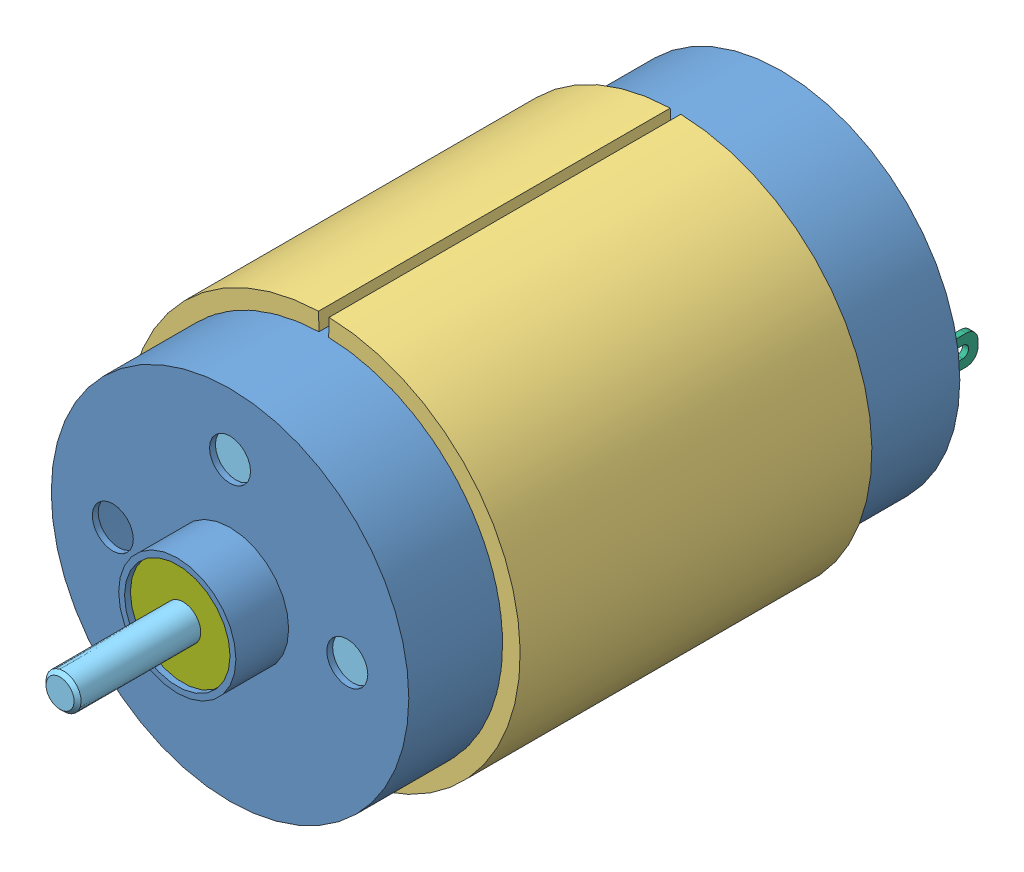
SolidWorks assembly motor 12v, configuration Default. Lengths in mm.
Overall size (33.5 33.49 67).
10 component instances, 7 part files, 27 mates.
Components (placement in the parent):
- Case 1-1: Case 1 [Default] at origin
- Case 2-1: Case 2 [Default] at (0 0 -22) x (1 0 0) z (0 0 -1)
- Case 3-1: Case 3 [Default] at (0 0 0.5) x (-1 0 0) z (0 0 1)
- Magnet-1: Magnet [Default] at (0 0 -1)
- Rotor-1: Rotor [Default] at (0 0 4.5) x (0.891833 0.452364 0) z (0 0 1)
- Magnet-2: Magnet [Default] at (0 0 -1) x (-1 0 0) z (0 0 1)
- Connect-1: Connect [Default] at (-11.75 0 -22) x (-1 0 0) z (0 0 1)
- Shaft Holder-1: Shaft Holder [Default] at (0 0 -27)
- Shaft Holder-2: Shaft Holder [Default] at (0 0 25.5) x (0.500475 0.865751 0) z (0 0 1)
- Connect-2: Connect [Default] at (11.75 0 -22)
Mates (geometry in assembly coordinates):
- Coincident1: coincident aligned: plane of Case 1-1 through (0 0 0) normal (0 0 1)
- Coincident2: coincident aligned: plane of Case 1-1 through (0 0 0) normal (0 1 0)
- Coincident3: coincident aligned: plane of Case 1-1 through (0 0 0) normal (1 0 0)
- Concentric1: concentric anti-aligned: cylinder of Case 1-1 through (0 0 23.5) axis (0 0 -1) radius 14.75; cylinder of Case 2-1 through (0 0 -23) axis (0 0 1) radius 14.75
- Coincident4: coincident anti-aligned: plane of Case 1-1 through (0 0 0) normal (0 1 0); plane of Case 2-1 through (0 0 -22) normal (0 -1 0)
- Distance1: distance = 0.5 mm aligned: plane of Case 2-1 through (0 0 -23) normal (0 0 -1); plane of Case 1-1 through (0 0 -23.5) normal (0 0 -1)
- Concentric2: concentric aligned: cylinder of Case 1-1 through (0 0 23.5) axis (0 0 -1) radius 15.25; cylinder of Case 3-1 through (0 0 15.5) axis (0 0 -1) radius 15.25
- Distance2: distance = 8 mm aligned: plane of Case 3-1 through (0 0 15.5) normal (0 0 1); plane of Case 1-1 through (0 0 23.5) normal (0 0 1)
- Coincident7: coincident anti-aligned: plane of Case 1-1 through (0 0 0) normal (0 1 0); plane of Case 3-1 through (0 0 0.5) normal (0 -1 0)
- Concentric6: concentric aligned: cylinder of Case 1-1 through (0 0 23.5) axis (0 0 -1) radius 14.75; cylinder of Magnet-1 through (0 0 14) axis (0 0 -1) radius 14.75
- Concentric7: concentric aligned: cylinder of Case 1-1 through (0 0 23.5) axis (0 0 -1) radius 14.75; cylinder of Magnet-2 through (0 0 14) axis (0 0 -1) radius 14.75
- Coincident13: coincident aligned: plane of Case 1-1 through (0 0 0) normal (0 1 0); plane of Magnet-1 through (0 0 -1) normal (0 1 0)
- Coincident14: coincident anti-aligned: plane of Case 1-1 through (0 0 0) normal (0 1 0); plane of Magnet-2 through (0 0 -1) normal (0 -1 0)
- Distance6: distance = 9 mm anti-aligned: plane of Case 1-1 through (0 0 23) normal (0 0 -1); plane of Magnet-1 through (0 0 14) normal (0 0 1)
- Distance7: distance = 9 mm anti-aligned: plane of Case 1-1 through (0 0 23) normal (0 0 -1); plane of Magnet-2 through (0 0 14) normal (0 0 1)
- Concentric8: concentric anti-aligned: cylinder of Magnet-1 through (0 0 14) axis (0 0 -1) radius 12.75; cylinder of Rotor-1 through (0 0 -13) axis (0 0 1) radius 12.25
- Distance8: distance = 3 mm aligned: plane of Rotor-1 through (0 0 17) normal (0 0 1); plane of Magnet-1 through (0 0 14) normal (0 0 1)
- Concentric9: concentric aligned: cylinder of Rotor-1 through (0 0 38) axis (0 0 -1) radius 1.5; cylinder of Shaft Holder-2 through (0 0 27.5) axis (0 0 -1) radius 1.5
- Distance9: distance = 0.5 mm aligned: plane of Shaft Holder-2 through (0 0 27.5) normal (0 0 1); plane of Case 1-1 through (0 0 28) normal (0 0 1)
- Concentric10: concentric aligned: cylinder of Rotor-1 through (0 0 38) axis (0 0 -1) radius 1.5; cylinder of Shaft Holder-1 through (0 0 -25) axis (0 0 -1) radius 1.5
- Distance10: distance = 0.5 mm aligned: plane of Shaft Holder-1 through (0 0 -27) normal (0 0 -1); plane of Case 2-1 through (0 0 -27.5) normal (0 0 -1)
- Coincident20: coincident anti-aligned: plane of Case 2-1 through (10 -3 -22) normal (1 0 0); plane of Connect-2 through (10 -3 -20) normal (-1 0 0)
- Coincident21: coincident anti-aligned: plane of Case 2-1 through (10 3 -22) normal (0 -1 0); plane of Connect-2 through (13.5 3 -20) normal (0 1 0)
- Coincident22: coincident anti-aligned: line of Case 2-1 through (10 3 -22) axis (1 0 0); line of Connect-2 through (13.5 3 -22) axis (-1 0 0)
- Coincident24: coincident: plane of Case 2-1 through (-10 -3 -22) normal (-1 0 0); plane of Connect-1 through (-10 3 -20) normal (1 0 0)
- Coincident25: coincident: plane of Case 2-1 through (-10 3 -22) normal (0 -1 0); plane of Connect-1 through (-13.5 3 -20) normal (0 1 0)
- Coincident26: coincident anti-aligned: line of Case 2-1 through (-13.5 3 -22) axis (1 0 0); line of Connect-1 through (-10 3 -22) axis (-1 0 0)
